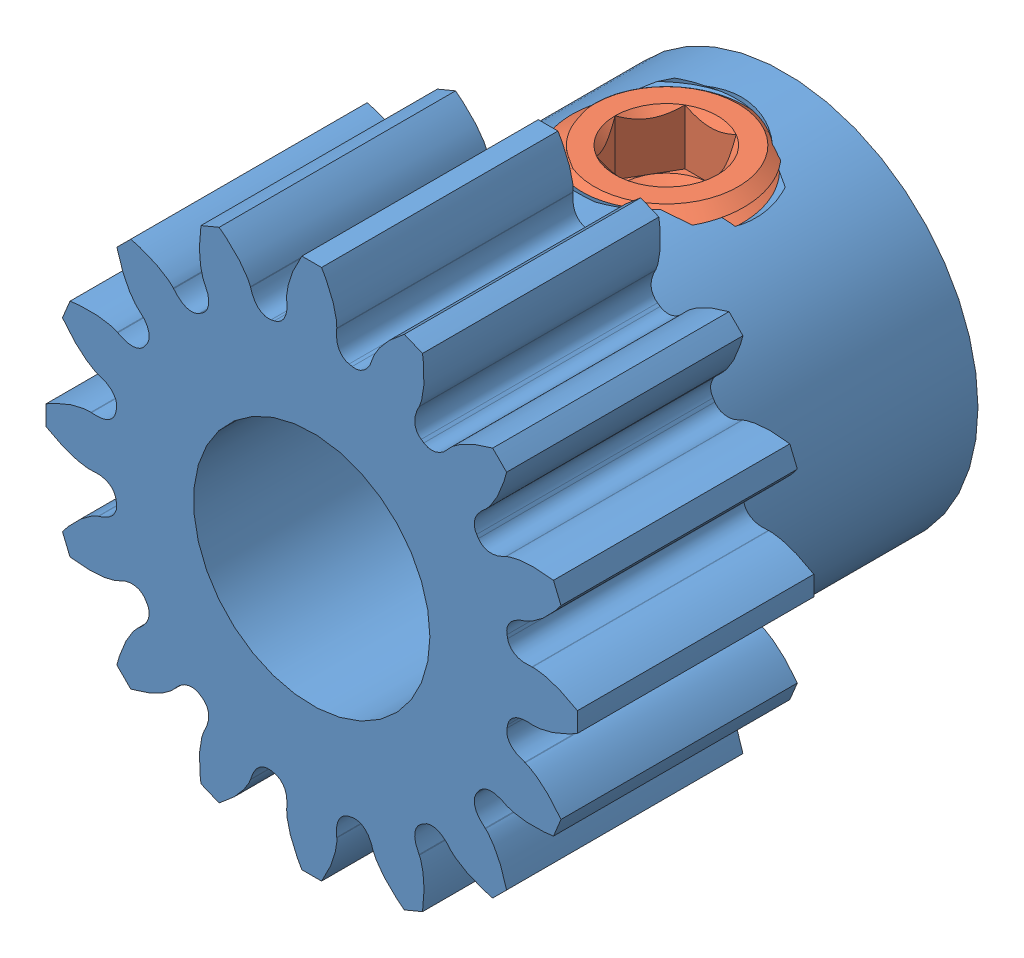
SolidWorks assembly 615242_SERVOCITY_GEAR_.250 SHAFT, configuration Default. Lengths in mm.
Overall size (14.29 14.29 12.89).
2 component instances, 2 part files, 0 mates.
Components (placement in the parent):
- 615242_Gear Blank-1: 615242_Gear Blank [Default] at (-35.6936 -35.8657 43.2017) size (14.29 14.29 12.7)
- 632134_91375A436-1: 632134_91375A436 [Default] at (-35.6936 -31.9694 40.0267) x (0.866032 0 0.499989) z (0 1 0) size (4.98 4.83 3.31)
